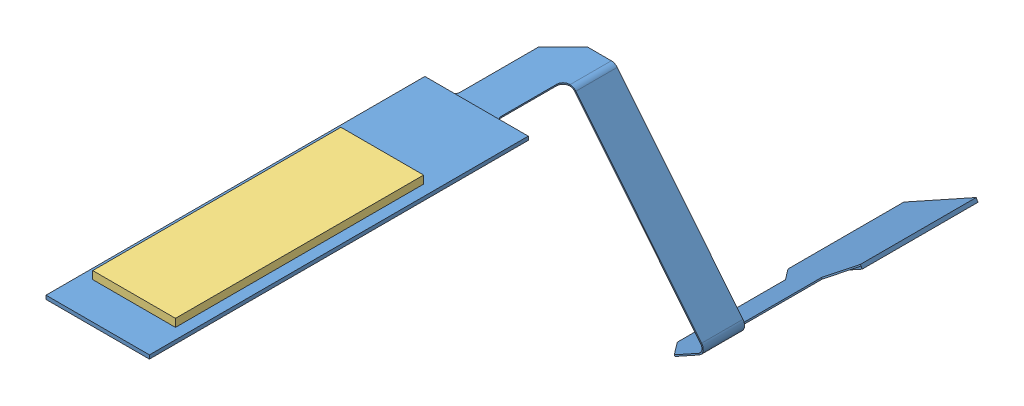
SolidWorks assembly PXL_Inner_Ladder_Driver_Board, configuration Bent. Lengths in mm.
Overall size (52.33 52.49 173).
3 component instances, 3 part files, 8 mates.
Components (placement in the parent):
- PXL_Inner_Ladder_Driver_Board-1: PXL_Inner_Ladder_Driver_Board [Bent] at origin size (52.33 50.59 173)
- 80pin_Socket_axt680224-1: 80pin_Socket_axt680224 [Default] at (31.0269 -45.0669 -270.43) x (0 0 -1) z (0.48481 -0.87462 0) size (17.8 2.6 1.01)
- PXL_Outer_Ladder_Driver_Chips_Envelope-1: PXL_Outer_Ladder_Driver_Chips_Envelope [Default] at (-0.1 0.58 -148.03) x (0 0 -1) z (1 0 0) size (60 1.9 20)
Mates (geometry in assembly coordinates):
- Coincident1: coordinate: point of PXL_Inner_Ladder_Driver_Board-1; point of assembly
- Distance5: distance = 1.8 mm anti-aligned: plane of 80pin_Socket_axt680224-1 through (31.5165 -45.9503 -279.33) normal (0.48481 -0.87462 0); plane of PXL_Inner_Ladder_Driver_Board-1 through (99.7388 -6.076 -109.13) normal (-0.48481 0.87462 0)
- Distance1: distance = 2.8 mm aligned: plane of 80pin_Socket_axt680224-1 through (30.7032 -46.4011 -279.33) normal (0 0 -1); plane of PXL_Inner_Ladder_Driver_Board-1 through (39.3901 -39.5278 -282.13) normal (0 0 -1)
- Distance2: distance = 10 mm: moEndPointRef_w of 80pin_Socket_axt680224-1; plane of PXL_Inner_Ladder_Driver_Board-1 through (39.3901 -39.5278 -254.13) normal (0.87462 0.48481 0)
- Coincident3: coincident anti-aligned: plane of PXL_Inner_Ladder_Driver_Board-1 through (-12.5 0.58 -109.13) normal (0 1 0); plane of PXL_Outer_Ladder_Driver_Chips_Envelope-1 through (-0.1 0.58 -148.03) normal (0 -1 0)
- Distance3: distance = 2.6 mm aligned: plane of PXL_Outer_Ladder_Driver_Chips_Envelope-1 through (9.9 2.48 -118.03) normal (1 0 0); plane of PXL_Inner_Ladder_Driver_Board-1 through (12.5 -0.32 -200.73) normal (1 0 0)
- Distance4: distance = 22.7 mm aligned: plane of PXL_Inner_Ladder_Driver_Board-1 through (-12.5 -0.32 -200.73) normal (0 0 -1); plane of PXL_Outer_Ladder_Driver_Chips_Envelope-1 through (-10.1 2.48 -178.03) normal (0 0 -1)
- Distance6: distance = 1.8 mm anti-aligned: plane of 80pin_Socket_axt680224-1 through (66.5 1.48 -279.33) normal (0 1 0); plane of PXL_Inner_Ladder_Driver_Board-1 through (-12.5 -0.32 -109.13) normal (0 -1 0)
